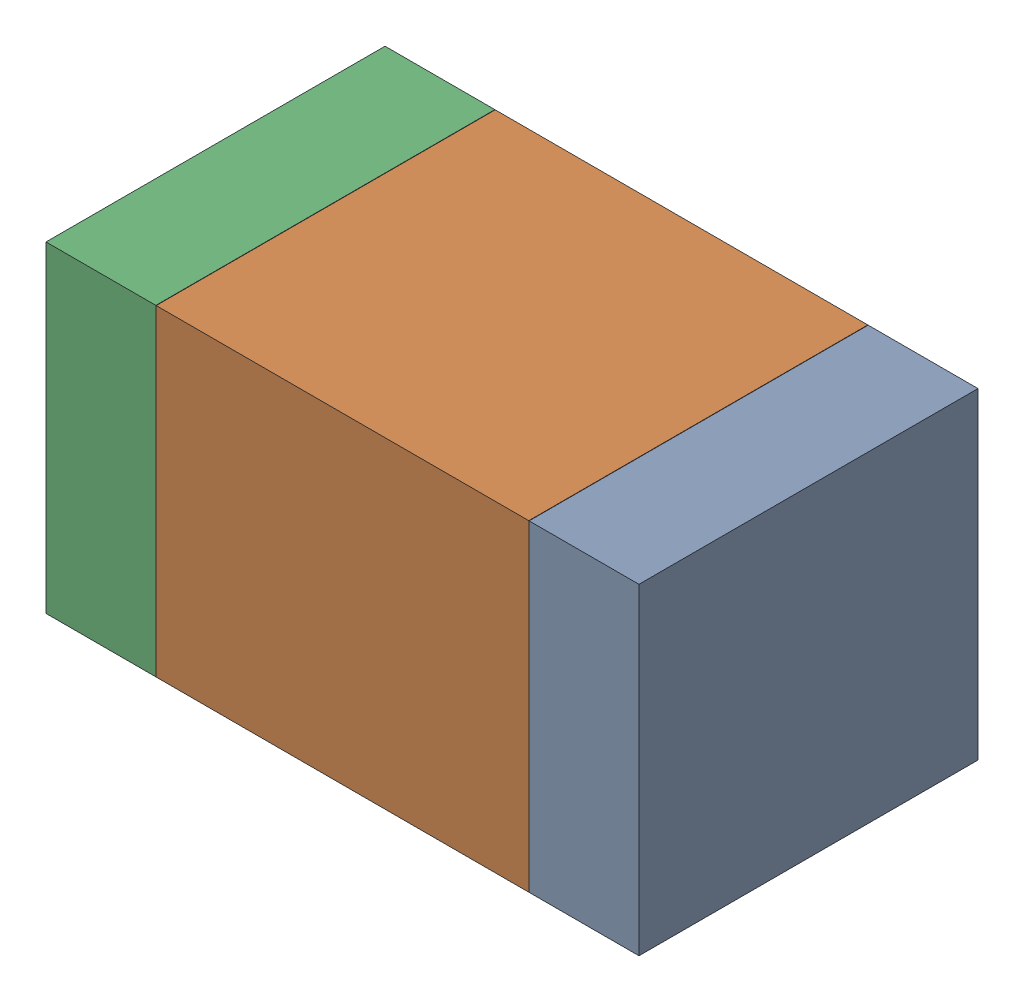
SolidWorks assembly R12, configuration Default. Lengths in mm.
Overall size (1.75 0.95 1).
6 component instances, 2 part files, 0 mates.
Components (placement in the parent):
- 6575498272-1: 6575498272 [Default] at (19.5085 22.479 0) size (0.32 0.95 1)
  - Extruded_8-1: Extruded_8 [Default] at origin size (0.32 0.95 1)
- 6575498112-1: 6575498112 [Default] at (18.796 22.479 0) size (1.1 0.95 1)
  - Extruded_9-1: Extruded_9 [Default] at origin size (1.1 0.95 1)
- 6575498272-2: 6575498272 [Default] at (18.0835 22.479 0) size (0.32 0.95 1)
  - Extruded_8-1: Extruded_8 [Default] at origin size (0.32 0.95 1)
